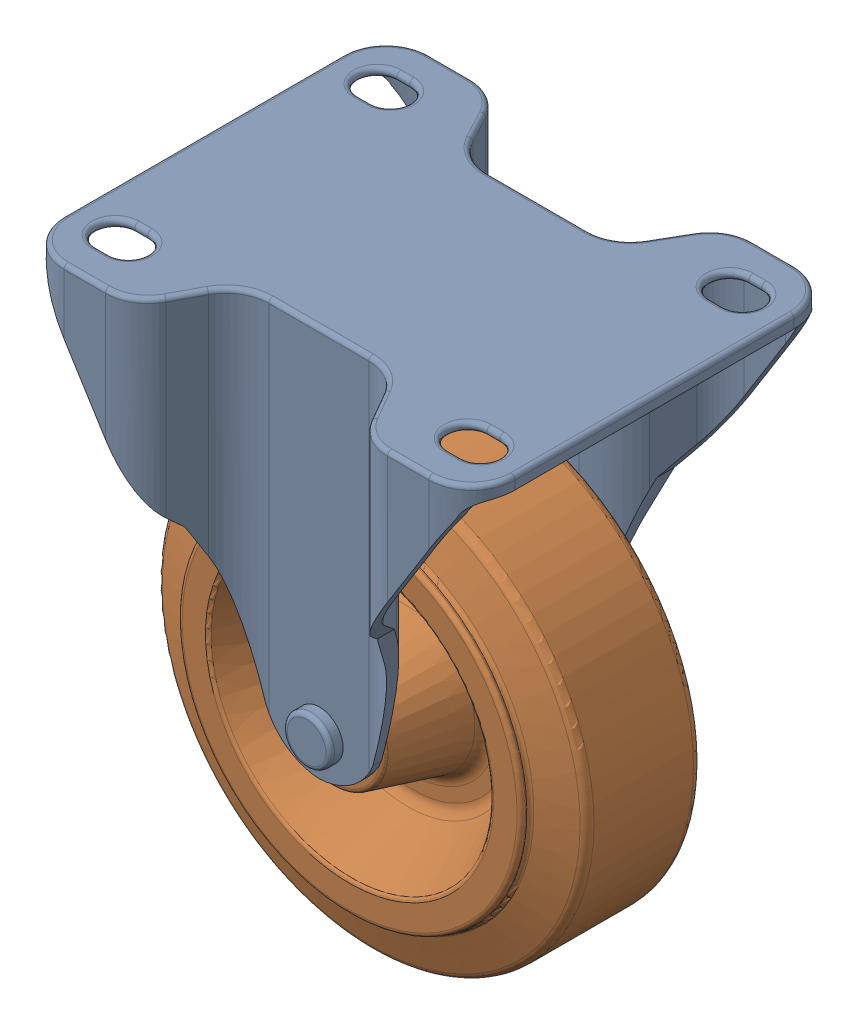
SolidWorks assembly 99999-004-01-00, configuration Default. Lengths in mm.
Overall size (124.53 144.27 85).
2 component instances, 2 part files, 0 mates.
Components (placement in the parent):
- 99999-004-01-02-1: 99999-004-01-02 [Default] at origin size (105 91 85)
- 99999-004-01-01-1: 99999-004-01-01 [Default] at (0 -82 -42.5) x (0 0 -1) z (-0.287519 0.957775 0) size (47 100 100)
